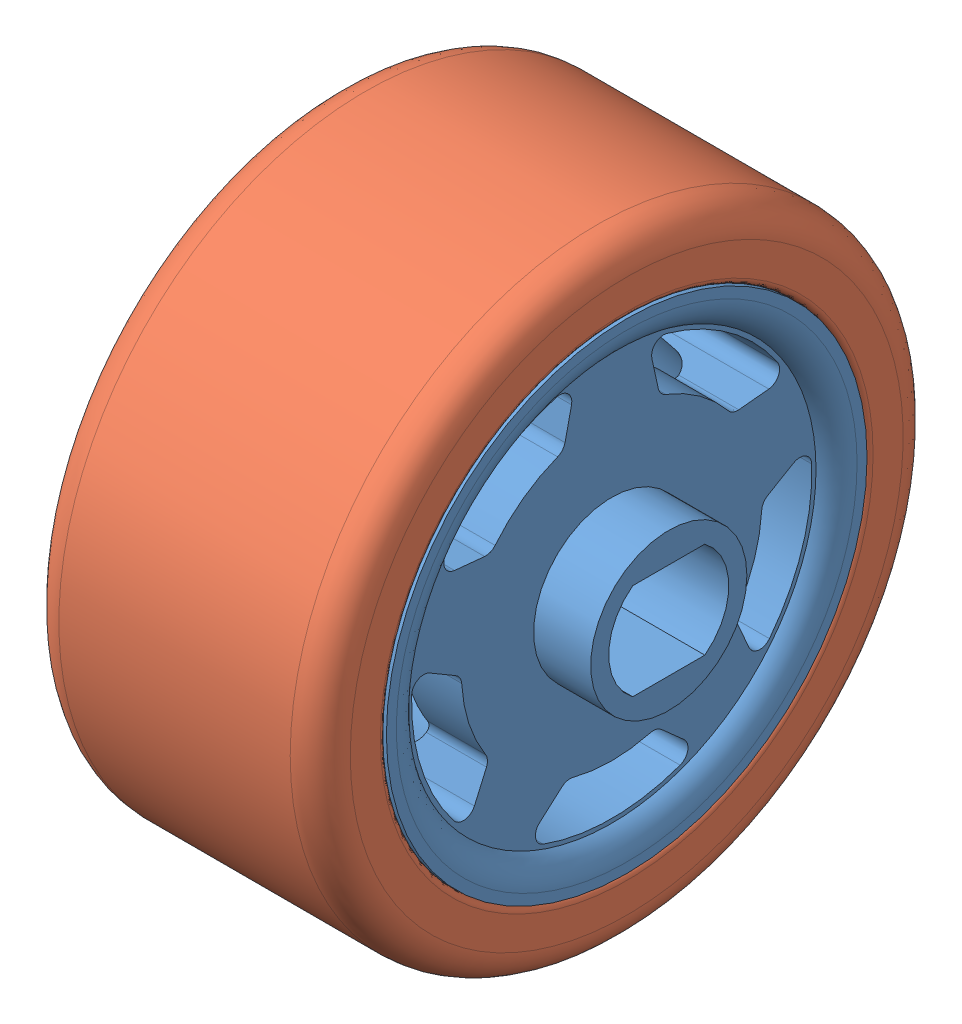
SolidWorks assembly _chassis_wheel_rear, configuration Default. Lengths in mm.
Overall size (27.75 51 51).
2 component instances, 2 part files, 2 mates.
Components (placement in the parent):
- chassis_wheel_center_back-1: chassis_wheel_center_back [Default] at (5.9936 1.7491 -4.3511) size (27.75 40 40)
- chassis_tire-1: chassis_tire [Default] at (-9.6314 1.7491 -4.3511) size (24.25 51 51)
Mates (geometry in assembly coordinates):
- Concentric1: concentric anti-aligned: cylinder of chassis_wheel_center_back-1 through (5.9936 1.7491 -4.3511) axis (1 0 0) radius 19; cylinder of chassis_tire-1 through (-9.6314 1.7491 -4.3511) axis (-1 0 0) radius 19
- Coincident1: coincident anti-aligned: plane of chassis_wheel_center_back-1 through (0.4936 1.7491 -24.3511) normal (-1 0 0); plane of chassis_tire-1 through (0.4936 1.7491 -23.3511) normal (1 0 0)
